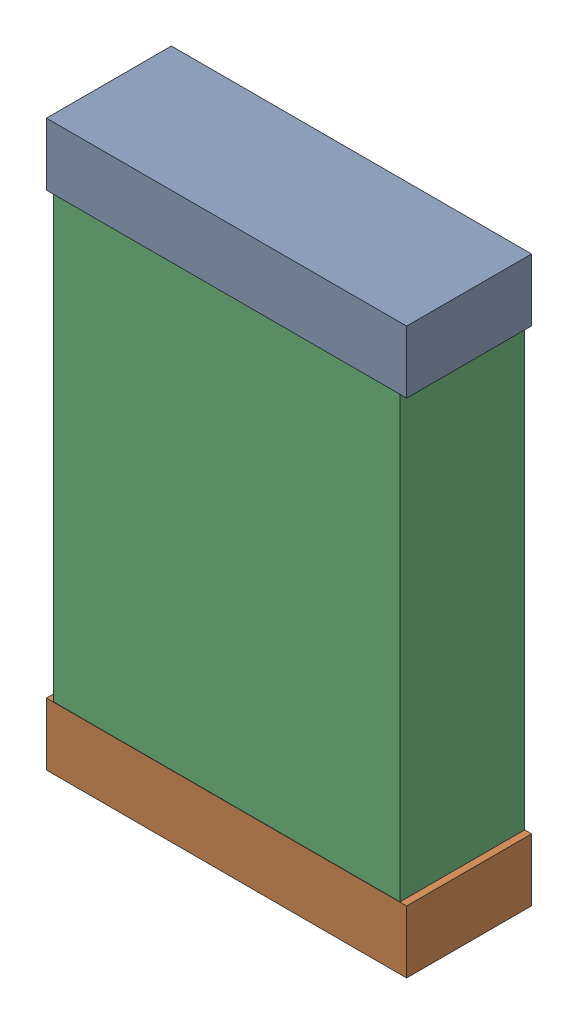
SolidWorks assembly C53, configuration Default. Lengths in mm.
Overall size (1.3 2.04 0.45).
6 component instances, 2 part files, 0 mates.
Components (placement in the parent):
- 740902240-1: 740902240 [Default] at (59.1812 17.9666 0) size (1.3 0.23 0.45)
  - Extruded_35-1: Extruded_35 [Default] at origin size (1.3 0.23 0.45)
- 740902240-2: 740902240 [Default] at (59.1812 16.1541 0) size (1.3 0.23 0.45)
  - Extruded_35-1: Extruded_35 [Default] at origin size (1.3 0.23 0.45)
- 740904480-1: 740904480 [Default] at (59.1812 17.0666 0) size (1.25 2 0.45)
  - Extruded_34-1: Extruded_34 [Default] at origin size (1.25 2 0.45)
